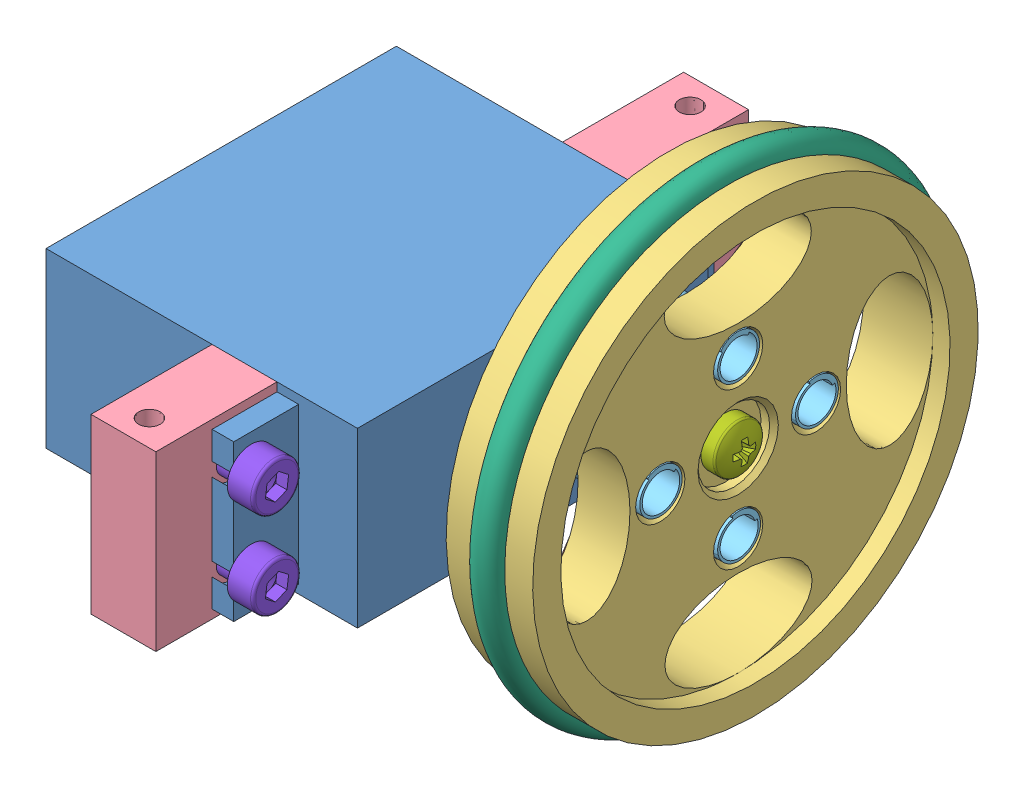
SolidWorks assembly 100001-10001-2-0, configuration Standard. Lengths in mm.
Overall size (52 72.83 80.42).
15 component instances, 8 part files, 28 mates.
Components (placement in the parent):
- 100001-10001-2-1-1: 100001-10001-2-1 [Standard] at (-15.2643 59.033 -6.3887) size (42 20 55.5)
- 100001-10001-2-2-1: 100001-10001-2-2 [Standard] at (8.7357 59.033 4.1113) x (0 0.707107 0.707107) z (1 0 0) size (38 38 6.2)
- 100001-10001-2-3-1: 100001-10001-2-3 [Standard] at (49.7891 52.1387 11.0056) x (1 0 0) z (0 0.707107 0.707107) size (10 51.5 51.5)
- 100001-10001-2-4-1: 100001-10001-2-4 [Standard] at (-14.0643 49.033 -20.3887) x (0 0 1) z (0 1 0) size (14 7.5 20)
- spring pin coiled_ld_din-1: spring pin coiled_ld_din [DIN EN ISO 8751-5x10-St] at (11.7357 50.2096 4.0219) x (0 -0.311365 0.95029) z (-1 0 0) size (5 5 10)
- spring pin coiled_ld_din-2: spring pin coiled_ld_din [DIN EN ISO 8751-5x10-St] at (11.7357 59.2127 -4.9719) x (0 -0.34461 0.938746) z (-1 0 0) size (5 5 10)
- spring pin coiled_ld_din-3: spring pin coiled_ld_din [DIN EN ISO 8751-5x10-St] at (11.7357 68.2288 4.141) x (0 -0.805079 0.593168) z (-1 0 0) size (5 5 10)
- spring pin coiled_ld_din-4: spring pin coiled_ld_din [DIN EN ISO 8751-5x10-St] at (11.7357 59.229 13.0834) x (0 -0.600355 0.799734) z (-1 0 0) size (5 5 10)
- o-rings series g_din-4: o-rings series g_din [O-ring DIN 3771 - 47.5x3.55] at (13.7391 59.033 4.1113) x (0 0.186008 -0.982548) z (1 0 0) size (54.6 54.6 3.55)
- pan head cross recess screw_din-1: pan head cross recess screw_din [ISO 7045 - M3 x 8 - Z --- 8N] at (17.6357 59.033 4.1113) x (-1 0 0) z (0 0.011789 0.999931) size (10.35 5.6 5.6)
- 100001-10001-2-4-2: 100001-10001-2-4 [Standard] at (-6.5643 49.033 48.1113) x (0 0 -1) z (0 1 0) size (14 7.5 20)
- socket head cap screw_din-1: socket head cap screw_din [DIN 912 M3 x 6 --- 6N] at (-1.0643 54.033 -11.8887) x (-1 0 0) z (0 0.924225 0.381849) size (9 5.5 5.5)
- socket head cap screw_din-2: socket head cap screw_din [DIN 912 M3 x 6 --- 6N] at (-1.0643 64.033 -11.8887) x (-1 0 0) z (0 0.924225 0.381849) size (9 5.5 5.5)
- socket head cap screw_din-3: socket head cap screw_din [DIN 912 M3 x 6 --- 6N] at (-1.0643 54.033 39.6113) x (-1 0 0) z (0 0.924225 0.381849) size (9 5.5 5.5)
- socket head cap screw_din-4: socket head cap screw_din [DIN 912 M3 x 6 --- 6N] at (-1.0643 64.033 39.6113) x (-1 0 0) z (0 0.924225 0.381849) size (9 5.5 5.5)
Mates (geometry in assembly coordinates):
- Konzentrisch1: concentric anti-aligned: cylinder of 100001-10001-2-1-1 through (8.7357 59.033 4.1113) axis (-1 0 0) radius 3; cylinder of 100001-10001-2-2-1 through (11.8462 59.033 4.1113) axis (1 0 0) radius 3
- Deckungsgleich1: coincident anti-aligned: plane of 100001-10001-2-1-1 through (8.7357 59.033 4.1113) normal (1 0 0); plane of 100001-10001-2-2-1 through (8.7357 50.033 4.1113) normal (-1 0 0)
- Konzentrisch2: concentric aligned: cylinder of 100001-10001-2-2-1 through (11.8462 59.033 4.1113) axis (1 0 0) radius 3.5; cylinder of 100001-10001-2-3-1 through (32.1262 59.033 4.1113) axis (1 0 0) radius 3.5
- Deckungsgleich2: coincident anti-aligned: plane of 100001-10001-2-2-1 through (10.7357 50.033 4.1113) normal (1 0 0); plane of 100001-10001-2-3-1 through (10.7357 72.468 -9.3237) normal (-1 0 0)
- Konzentrisch3: concentric aligned: circle of 100001-10001-2-2-1; circle of 100001-10001-2-3-1
- Konzentrisch11: concentric anti-aligned: cylinder of 100001-10001-2-3-1 through (8.7357 50.033 4.1113) axis (-1 0 0) radius 2.35; cylinder of spring pin coiled_ld_din-1 through (6.7357 50.033 4.1113) axis (1 0 0) radius 2.3641
- Konzentrisch12: concentric anti-aligned: cylinder of 100001-10001-2-3-1 through (8.7357 59.033 -4.8887) axis (-1 0 0) radius 2.35; cylinder of spring pin coiled_ld_din-2 through (6.7357 59.033 -4.8887) axis (1 0 0) radius 2.3641
- Konzentrisch13: concentric anti-aligned: cylinder of 100001-10001-2-3-1 through (8.7357 59.033 13.1113) axis (-1 0 0) radius 2.35; cylinder of spring pin coiled_ld_din-4 through (6.7357 59.033 13.1113) axis (1 0 0) radius 2.3641
- Konzentrisch14: concentric anti-aligned: cylinder of 100001-10001-2-3-1 through (8.7357 68.033 4.1113) axis (-1 0 0) radius 2.35; cylinder of spring pin coiled_ld_din-3 through (6.7357 68.033 4.1113) axis (1 0 0) radius 2.3641
- Deckungsgleich3: coincident aligned: plane of spring pin coiled_ld_din-2 through (16.7357 59.033 -4.8887) normal (1 0 0); plane of spring pin coiled_ld_din-1 through (16.7357 50.033 4.1113) normal (1 0 0)
- Deckungsgleich4: coincident aligned: plane of spring pin coiled_ld_din-2 through (16.7357 59.033 -4.8887) normal (1 0 0); plane of spring pin coiled_ld_din-4 through (16.7357 59.033 13.1113) normal (1 0 0)
- Deckungsgleich5: coincident aligned: plane of spring pin coiled_ld_din-2 through (16.7357 59.033 -4.8887) normal (1 0 0); plane of spring pin coiled_ld_din-3 through (16.7357 68.033 4.1113) normal (1 0 0)
- Deckungsgleich6: coincident aligned: plane of spring pin coiled_ld_din-2 through (16.7357 59.033 -4.8887) normal (1 0 0); plane of 100001-10001-2-3-1 through (16.7357 74.9429 -11.7986) normal (1 0 0)
- Deckungsgleich9: coincident anti-aligned: plane of 100001-10001-2-1-1 through (-6.5643 50.033 -13.8887) normal (-1 0 0); plane of 100001-10001-2-4-1 through (-6.5643 69.033 -20.3887) normal (1 0 0)
- Deckungsgleich10: coincident anti-aligned: plane of 100001-10001-2-1-1 through (-15.2643 59.033 -6.3887) normal (0 0 -1); plane of 100001-10001-2-4-1 through (-6.5643 69.033 -6.3887) normal (0 0 1)
- Deckungsgleich11: coincident aligned: plane of 100001-10001-2-1-1 through (-33.2643 49.033 34.1113) normal (0 -1 0); plane of 100001-10001-2-4-1 through (-14.0643 49.033 -20.3887) normal (0 -1 0)
- Deckungsgleich12: coincident anti-aligned: axis of 100001-10001-2-3-1 through (-0.848 59.033 4.1113) axis (1 0 0); axis of o-rings series g_din-4 through (29.1986 59.033 4.1113) axis (-1 0 0)
- Deckungsgleich13: coincident aligned: plane of 100001-10001-2-3-1; plane of o-rings series g_din-4 through (13.7391 59.033 4.1113) normal (1 0 0)
- Deckungsgleich14: coincident aligned: circle of 100001-10001-2-3-1; circle of pan head cross recess screw_din-1
- Konzentrisch16: concentric aligned: cylinder of 100001-10001-2-1-1 through (-4.0643 54.033 -11.8887) axis (1 0 0) radius 2.15; cylinder of socket head cap screw_din-1 through (30.6857 54.033 -11.8887) axis (1 0 0) radius 2.75
- Deckungsgleich15: coincident anti-aligned: plane of 100001-10001-2-1-1 through (-4.0643 50.033 -13.8887) normal (1 0 0); plane of socket head cap screw_din-1 through (-4.0643 52.9829 -9.3471) normal (-1 0 0)
- Konzentrisch17: concentric aligned: cylinder of 100001-10001-2-1-1 through (-4.0643 64.033 -11.8887) axis (1 0 0) radius 2.15; cylinder of socket head cap screw_din-2 through (30.6857 64.033 -11.8887) axis (1 0 0) radius 2.75
- Deckungsgleich16: coincident anti-aligned: plane of 100001-10001-2-1-1 through (-4.0643 50.033 -13.8887) normal (1 0 0); plane of socket head cap screw_din-2 through (-4.0643 62.9829 -9.3471) normal (-1 0 0)
- Konzentrisch18: concentric aligned: cylinder of 100001-10001-2-1-1 through (-4.0643 54.033 39.6113) axis (1 0 0) radius 2.15; cylinder of socket head cap screw_din-3 through (30.6857 54.033 39.6113) axis (1 0 0) radius 2.75
- Deckungsgleich17: coincident anti-aligned: plane of 100001-10001-2-1-1 through (-4.0643 50.033 41.6113) normal (1 0 0); plane of socket head cap screw_din-3 through (-4.0643 52.9829 42.1529) normal (-1 0 0)
- Konzentrisch19: concentric aligned: cylinder of 100001-10001-2-1-1 through (-4.0643 64.033 39.6113) axis (1 0 0) radius 2.15; cylinder of socket head cap screw_din-4 through (30.6857 64.033 39.6113) axis (1 0 0) radius 2.75
- Deckungsgleich18: coincident anti-aligned: plane of 100001-10001-2-1-1 through (-4.0643 50.033 41.6113) normal (1 0 0); plane of socket head cap screw_din-4 through (-4.0643 62.9829 42.1529) normal (-1 0 0)
- Winkel1: planar angle = 0.785398 rad aligned: plane of 100001-10001-2-3-1 through (49.7891 52.1387 11.0056) normal (0 0.707107 0.707107); plane of 100001-10001-2-1-1 through (-33.2643 69.033 34.1113) normal (0 1 0)
